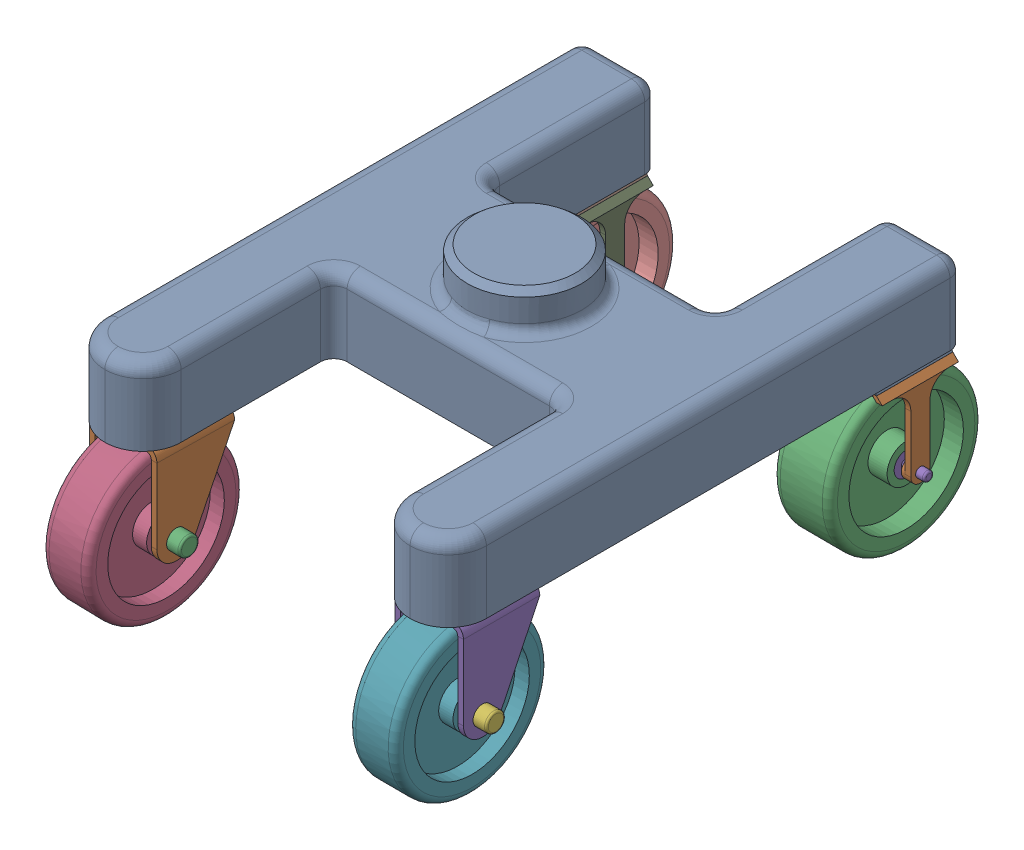
SolidWorks assembly car_final, configuration Default. Lengths in mm.
Overall size (543.56 378.72 789.08).
21 component instances, 8 part files, 10 mates.
Components (placement in the parent):
- Chassis-1: Chassis [Default] at (356.6038 747.5628 577.1345) size (508 152.4 685.8)
- Front Wheel-1: Front Wheel [Default] at (365.3595 654.408 1122.3852) x (0.999827 0 0.018618) z (-0.018618 0 0.999827) size (127 266.82 205.91)
  - FW Support-2: FW Support [Default] at (46.0725 -79.0572 215.9289) size (91.44 189.99 101.6)
  - FW Shaft-2: FW Shaft [Default] at (46.0725 -20.6372 241.3289) size (127 31.75 31.75)
  - FW Wheel-2: FW Wheel [Default] at (46.0725 -20.6372 241.3289) x (1 0 0) z (0 -0.013412 -0.99991) size (63.5 203.2 203.2)
- Front Wheel-2: Front Wheel [Default] at (767.7314 654.408 1123.2056) size (127 266.82 205.91)
  - FW Support-2: FW Support [Default] at (46.0725 -79.0572 215.9289) size (91.44 189.99 101.6)
  - FW Shaft-2: FW Shaft [Default] at (46.0725 -20.6372 241.3289) size (127 31.75 31.75)
  - FW Wheel-2: FW Wheel [Default] at (46.0725 -20.6372 241.3289) x (1 0 0) z (0 -0.013412 -0.99991) size (63.5 203.2 203.2)
- Backwheel-1: Backwheel [Default] at (310.5153 851.5922 939.2722) x (1 0 0) z (0 0 -1) size (137.16 277.12 226.77)
  - Base-1: Base [Default] at (96.8885 104.0294 146.2377) size (98.97 58.42 101.6)
  - Back Wheel Support-1: Back Wheel Support [Default] at (166.7385 108.4744 146.2377) x (0 0 -1) z (1 0 0) size (101.6 121.92 12.7)
  - Wheel-1: Wheel [Default] at (96.8885 217.6944 146.2377) x (1 0 0) z (0 0.123644 0.992327) size (76.2 203.2 203.2)
  - Back Wheel Support-2: Back Wheel Support [Default] at (27.0385 108.4744 146.2377) x (0 0 1) z (-1 0 0) size (101.6 121.92 12.7)
  - Shaft-2: Shaft [Default] at (96.8885 217.6944 146.2377) x (1 0 0) z (0 -0.212383 0.977187) size (137.16 31.75 31.75)
- Backwheel-2: Backwheel [Default] at (716.9153 851.5922 939.2722) x (1 0 0) z (0 0 -1) size (137.16 277.12 226.77)
  - Base-1: Base [Default] at (96.8885 104.0294 146.2377) size (98.97 58.42 101.6)
  - Back Wheel Support-1: Back Wheel Support [Default] at (166.7385 108.4744 146.2377) x (0 0 -1) z (1 0 0) size (101.6 121.92 12.7)
  - Wheel-1: Wheel [Default] at (96.8885 217.6944 146.2377) x (1 0 0) z (0 0.123644 0.992327) size (76.2 203.2 203.2)
  - Back Wheel Support-2: Back Wheel Support [Default] at (27.0385 108.4744 146.2377) x (0 0 1) z (-1 0 0) size (101.6 121.92 12.7)
  - Shaft-2: Shaft [Default] at (96.8885 217.6944 146.2377) x (1 0 0) z (0 -0.212383 0.977187) size (137.16 31.75 31.75)
Mates (geometry in assembly coordinates):
- Concentric1: concentric aligned: cylinder of Chassis-1 through (813.8038 798.3628 1339.1345) axis (0 -1 0) radius 25.4; cylinder of Front Wheel-2/FW Support-2 through (813.8038 798.3628 1339.1345) axis (0 -1 0) radius 25.3618
- Coincident1: coincident anti-aligned: plane of Chassis-1 through (813.8038 798.3628 1339.1345) normal (0 -1 0); plane of Front Wheel-2/FW Support-2 through (813.8038 798.3628 1339.1345) normal (0 1 0)
- Concentric2: concentric aligned: cylinder of Chassis-1 through (407.4038 798.3628 1339.1345) axis (0 -1 0) radius 25.4; cylinder of Front Wheel-1/FW Support-2 through (407.4038 798.3628 1339.1345) axis (0 -1 0) radius 25.3618
- Coincident2: coincident anti-aligned: plane of Chassis-1 through (407.4038 798.3628 1339.1345) normal (0 -1 0); plane of Front Wheel-1/FW Support-2 through (407.4038 798.3628 1339.1345) normal (0 1 0)
- Coincident3: coincident anti-aligned: plane of Chassis-1 through (394.7038 798.3628 780.3345) normal (1 0 0); plane of Backwheel-1/Base-1 through (394.7038 798.3628 780.3345) normal (-1 0 0)
- Coincident4: coincident anti-aligned: plane of Chassis-1 through (420.1038 798.3628 780.3345) normal (0 0 1); plane of Backwheel-1/Base-1 through (394.7038 798.3628 780.3345) normal (0 0 -1)
- Coincident5: coincident anti-aligned: plane of Chassis-1 through (356.6038 798.3628 577.1345) normal (0 -1 0); plane of Backwheel-1/Base-1 through (407.4038 798.3628 793.0345) normal (0 1 0)
- Coincident6: coincident anti-aligned: plane of Chassis-1 through (356.6038 798.3628 577.1345) normal (0 -1 0); plane of Backwheel-2/Base-1 through (813.8038 798.3628 793.0345) normal (0 1 0)
- Coincident7: coincident anti-aligned: plane of Chassis-1 through (826.5038 798.3628 805.7345) normal (0 0 -1); plane of Backwheel-2/Base-1 through (801.1038 798.3628 805.7345) normal (0 0 1)
- Coincident9: coincident anti-aligned: plane of Chassis-1 through (826.5038 798.3628 805.7345) normal (-1 0 0); plane of Backwheel-2/Base-1 through (826.5038 798.3628 780.3345) normal (1 0 0)
